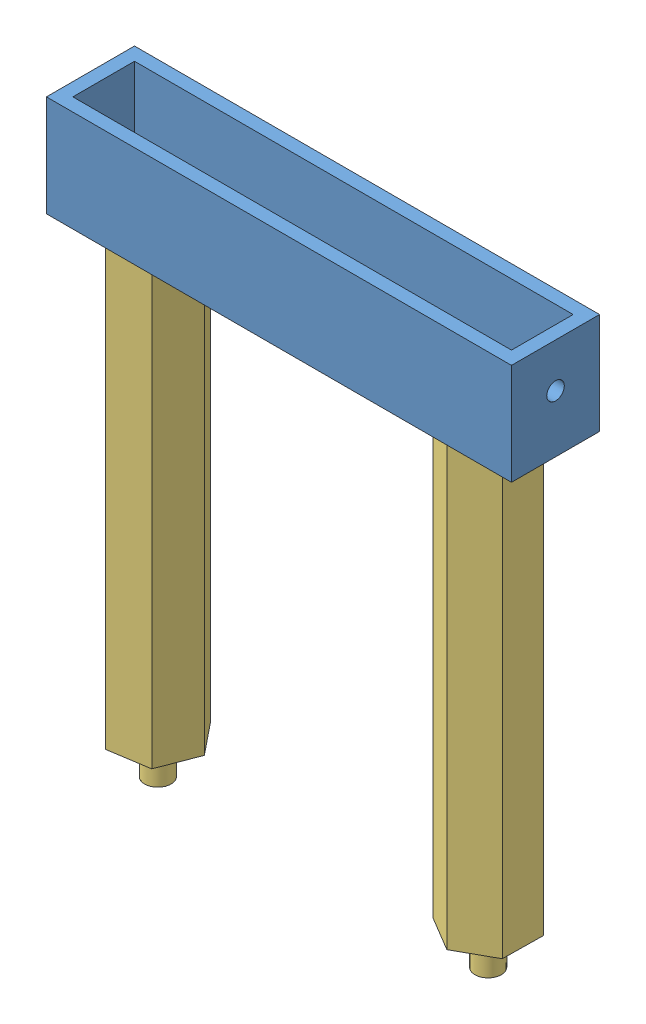
SolidWorks assembly 出绳链接件（100）+单头六角柱100, configuration Default. Lengths in mm.
Overall size (105.6 131 24.43).
6 component instances, 3 part files, 4 mates.
Components (placement in the parent):
- 出绳点链接板（100）-1: 出绳点链接板（100） [默认] at (-53.5022 -44.1551 -44.4975) size (105.6 31 20)
  - 出绳点链接板（100）-1: 出绳点链接板（100） [默认] at (-3.3008 48.9416 89.016) size (105.6 23 20)
  - 柱塞螺丝M6-1: 柱塞螺丝M6 [默认] at (-40.8008 55.6816 89.016) x (-0.837169 0 -0.546944) z (-0.546944 0 0.837169) size (12 14.74 12)
  - 柱塞螺丝M6-2: 柱塞螺丝M6 [默认] at (34.1992 55.6816 89.016) x (-0.837169 0 -0.546944) z (-0.546944 0 0.837169) size (12 14.74 12)
- 单头六角柱100-1: 单头六角柱100 [默认] at (-94.303 4.7865 44.5185) x (-0.629053 0 -0.777362) z (-0.777362 0 0.629053) size (18.48 108 16.01)
- 单头六角柱100-2: 单头六角柱100 [默认] at (-19.303 4.7865 44.5185) x (-0.859584 0 -0.510994) z (-0.510994 0 0.859584) size (18.48 108 16.01)
Mates (geometry in assembly coordinates):
- 同心1: concentric aligned: cylinder of 出绳点链接板（100）-1/柱塞螺丝M6-1 through (-94.303 -3.2135 44.5185) axis (0 1 0) radius 3; cylinder of 单头六角柱100-1 through (-94.303 -3.2135 44.5185) axis (0 1 0) radius 3
- 同心2: concentric aligned: cylinder of 出绳点链接板（100）-1/柱塞螺丝M6-2 through (-19.303 -3.2135 44.5185) axis (0 1 0) radius 3; cylinder of 单头六角柱100-2 through (-19.303 -3.2135 44.5185) axis (0 1 0) radius 3
- 重合1: coincident aligned: plane of 单头六角柱100-1 through (-94.303 4.7865 44.5185) normal (0 1 0); plane of 单头六角柱100-2 through (-19.303 4.7865 44.5185) normal (0 1 0)
- 重合2: coincident anti-aligned: plane of 出绳点链接板（100）-1/出绳点链接板（100）-1 through (-56.803 4.7865 44.5185) normal (0 -1 0); plane of 单头六角柱100-1 through (-94.303 4.7865 44.5185) normal (0 1 0)
